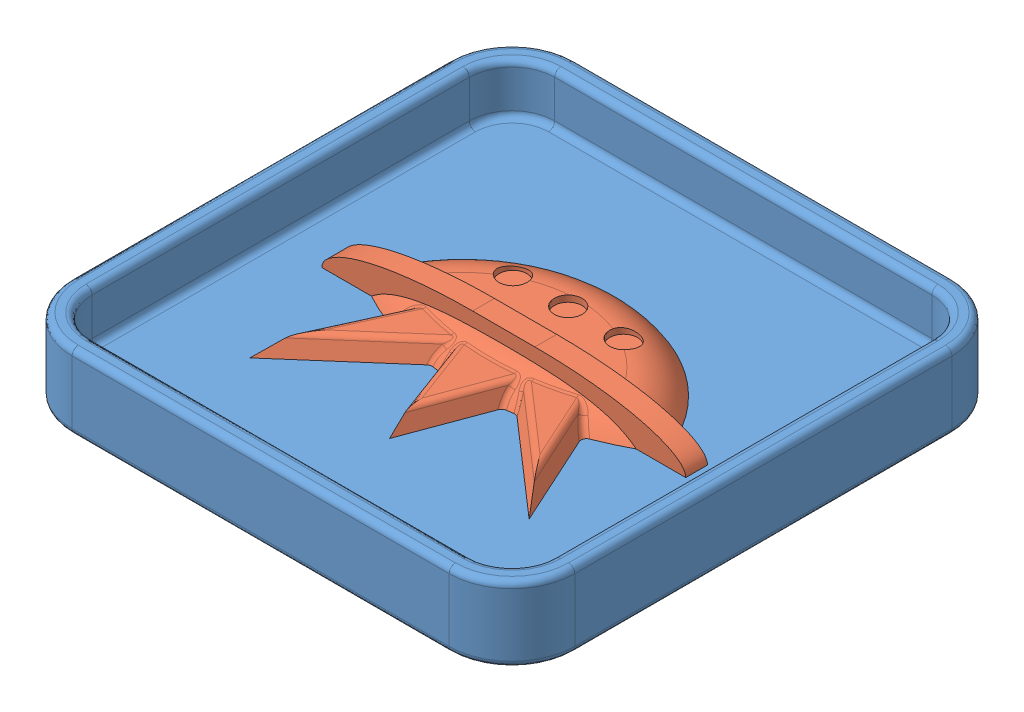
SolidWorks assembly Assem5, configuration Default. Lengths in mm.
Overall size (40 6 40).
2 component instances, 2 part files, 2 mates.
Components (placement in the parent):
- Tile-1: Tile [Default] at (8.8743 16.196 35.0395) size (40 6 40)
- GreenSpaceship-1: GreenSpaceship [Default] at (8.6865 18.196 34.6395) size (28.98 4.89 18.53)
Mates (geometry in assembly coordinates):
- Coincident1: coincident anti-aligned: plane of Tile-1 through (-6.1257 18.196 50.0395) normal (0 1 0); plane of GreenSpaceship-1 through (8.6865 18.196 34.6395) normal (0 -1 0)
- Coincident2: coincident anti-aligned: line of Tile-1 through (23.8743 18.196 17.1395) axis (-1 0 0); line of GreenSpaceship-1 through (-8.8135 18.196 17.1395) axis (1 0 0)
